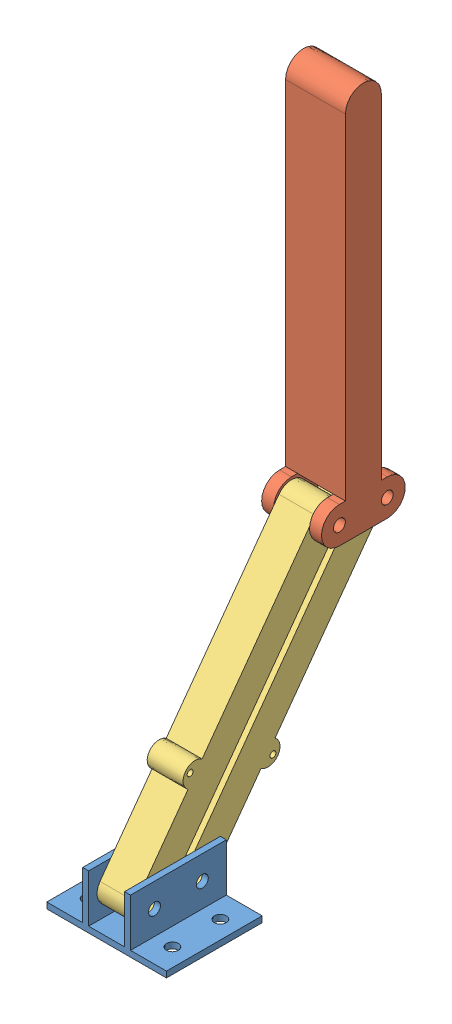
SolidWorks assembly Arm Assem, configuration Default. Lengths in mm.
Overall size (63.5 343.12 153.67).
4 component instances, 3 part files, 8 mates.
Components (placement in the parent):
- Mounting Bracket-1: Mounting Bracket [Default] at origin size (63.5 28.57 50.8)
- Contact Arm-1: Contact Arm [Default] at (15.875 146.265 -82.2364) x (0 1 0) z (1 0 0) size (206.38 44.45 31.75)
- Parallel Arm-2: Parallel Arm [Default] at (41.275 81.07 -9.3682) x (0 0.80842 -0.588607) z (0 0.588607 0.80842) size (177.8 19.05 22.86)
- Parallel Arm-5: Parallel Arm [Default] at (22.225 81.07 -34.7682) x (0 0.80842 -0.588607) z (0 -0.588607 -0.80842) size (177.8 19.05 22.86)
Mates (geometry in assembly coordinates):
- Concentric2: concentric: cylinder of Mounting Bracket-1 through (63.5 15.875 38.1) axis (-1 0 0) radius 3.175; cylinder of Parallel Arm-2 through (22.225 15.875 38.1) axis (1 0 0) radius 3.175
- Coincident2: coincident: plane of Mounting Bracket-1 through (22.225 3.175 50.8) normal (1 0 0); plane of Parallel Arm-2 through (22.225 15.875 38.1) normal (-1 0 0)
- Concentric5: concentric: cylinder of Contact Arm-1 through (47.625 146.265 -56.8364) axis (-1 0 0) radius 3.175; cylinder of Parallel Arm-2 through (22.225 146.265 -56.8364) axis (1 0 0) radius 3.175
- Parallel1: parallel: plane of Parallel Arm-2 through (22.225 11.0161 31.4265) normal (0 -0.588607 -0.80842); plane of Parallel Arm-5 through (41.275 20.7339 19.3735) normal (0 0.588607 0.80842)
- Concentric8: concentric: cylinder of Mounting Bracket-1 through (63.5 15.875 12.7) axis (-1 0 0) radius 3.175; cylinder of Parallel Arm-5 through (41.275 15.875 12.7) axis (-1 0 0) radius 3.175
- Coincident6: coincident: plane of Mounting Bracket-1 through (22.225 3.175 50.8) normal (1 0 0); plane of Parallel Arm-5 through (22.225 15.875 12.7) normal (-1 0 0)
- Coincident7: coincident: plane of Contact Arm-1 through (22.225 155.79 -82.2364) normal (1 0 0); plane of Parallel Arm-5 through (22.225 15.875 12.7) normal (-1 0 0)
- Concentric9: concentric: cylinder of Contact Arm-1 through (47.625 146.265 -82.2364) axis (-1 0 0) radius 3.175; cylinder of Parallel Arm-5 through (41.275 146.265 -82.2364) axis (-1 0 0) radius 3.175
